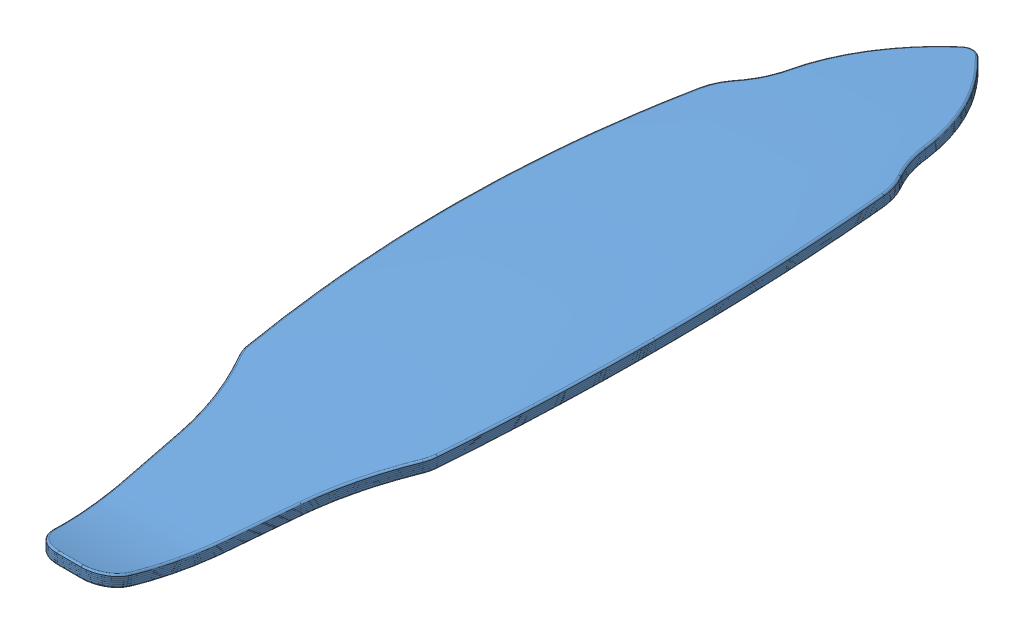
SolidWorks assembly Chamber Deck, configuration Default. Lengths in mm.
Overall size (203.4 42.87 846.49).
7 component instances, 1 part files, 18 mates.
Components (placement in the parent):
- ply-1: ply [Default] at origin size (203.2 22.83 841.38)
- ply-2: ply [Default] at (0 1.5804 0) size (203.2 22.83 841.38)
- ply-3: ply [Default] at (0 3.1608 0) size (203.2 22.83 841.38)
- ply-4: ply [Default] at (0 4.7412 0) size (203.2 22.83 841.38)
- ply-5: ply [Default] at (0 6.3215 0) size (203.2 22.83 841.38)
- ply-6: ply [Default] at (0 7.9019 0) size (203.2 22.83 841.38)
- ply-7: ply [Default] at (0 9.4823 0) size (203.2 22.83 841.38)
Mates (geometry in assembly coordinates):
- Coincident23: coincident: point of ply-1; point of ply-2
- Coincident24: coincident: point of ply-1; point of ply-2
- Coincident25: coincident: point of ply-1; point of ply-2
- Coincident26: coincident: point of ply-2; point of ply-3
- Coincident27: coincident: point of ply-3; point of ply-4
- Coincident28: coincident: point of ply-4; point of ply-5
- Coincident29: coincident: point of ply-5; point of ply-6
- Coincident30: coincident: point of ply-6; point of ply-7
- Coincident31: coincident: point of ply-2; point of ply-3
- Coincident32: coincident: point of ply-3; point of ply-4
- Coincident33: coincident: point of ply-4; point of ply-5
- Coincident34: coincident: point of ply-5; point of ply-6
- Coincident35: coincident: point of ply-6; point of ply-7
- Coincident36: coincident: point of ply-2; point of ply-3
- Coincident37: coincident: point of ply-3; point of ply-4
- Coincident38: coincident: point of ply-4; point of ply-5
- Coincident39: coincident: point of ply-5; point of ply-6
- Coincident40: coincident: point of ply-6; point of ply-7
